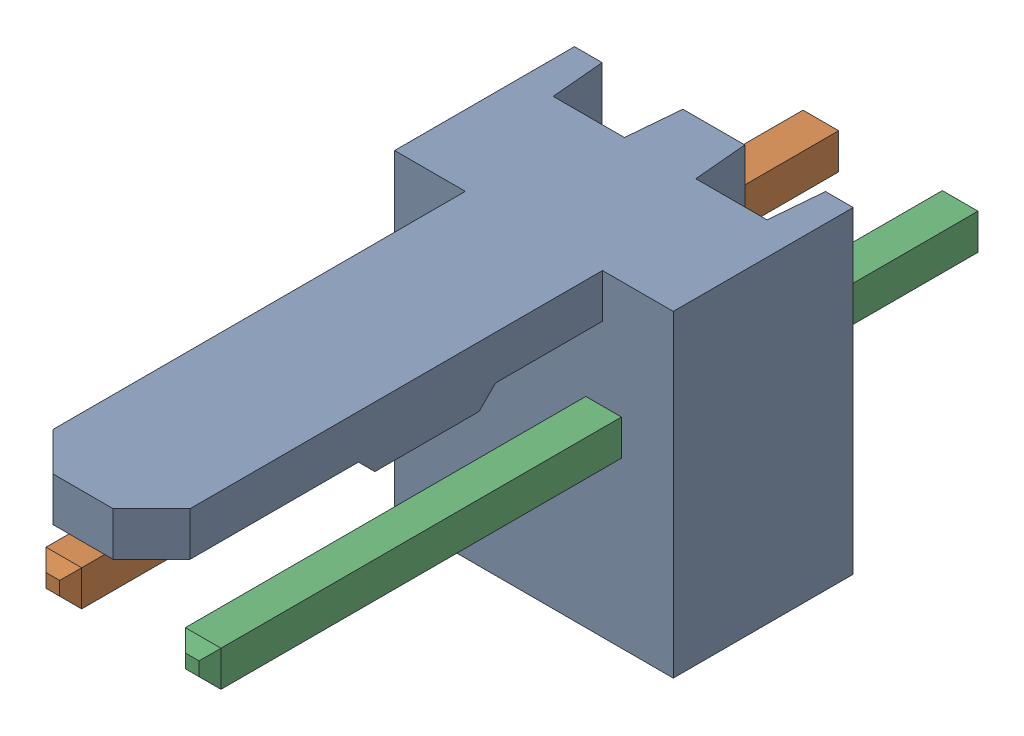
SolidWorks assembly Molex PCB 2 pin v2_4, configuration Default. Lengths in mm.
Overall size (5.08 5.79 14.92).
3 component instances, 2 part files, 0 mates.
Components (placement in the parent):
- BASE9710016_1-1: BASE9710016_1 [Default] at (2.54 2.895 -8.22) size (5.08 5.79 11.5)
- PINO9710016_1-1: PINO9710016_1 [Default] at (1.27 3.325 -0.72) size (0.65 0.65 14.2)
- PINO9710016_1-2: PINO9710016_1 [Default] at (3.81 3.325 -0.72) size (0.65 0.65 14.2)
